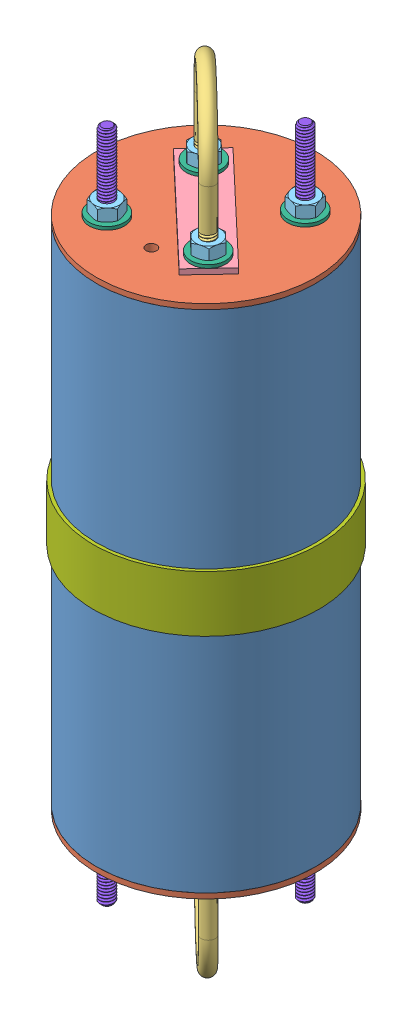
SolidWorks assembly EBayAssembly, configuration Default. Lengths in mm.
Overall size (140.1 352.48 140.1).
55 component instances, 10 part files, 79 mates.
Components (placement in the parent):
- EBayCoupler-1: EBayCoupler [Default] at (144.2445 84.1878 268.749) size (99.1 228.6 99.1)
- EBayBulkheadAssembly-1: EBayBulkheadAssembly [Default] at (219.6286 370.3293 234.3006) x (-0.726253 0 -0.687428) z (-0.687428 0 0.726253) size (99.1 83.11 99.1)
  - EBayBulkhead-1: EBayBulkhead [Default] at (31.0671 55.1815 76.8393) size (99.1 4.72 99.1)
  - 3043T618_U-Bolt-1: 3043T618_U-Bolt [3043T618] at (31.0671 24.1754 76.8393) size (63.63 83.11 11.11)
  - 8875T929_Mount Plate for 1 4 -20 Thread-1: 8875T929_Mount Plate for 1 4 -20 Thread [8875T929] at (31.0671 59.9015 76.8393) x (1 0 0) z (0 1 0) size (66.67 19.05 2.38)
  - 91845A029_18-8 Stainless Steel Hex Nut-1: 91845A029_18-8 Stainless Steel Hex Nut [91845A029] at (5.6671 48.5743 76.8393) x (0.866025 0 0.5) z (0 -1 0) size (11.11 12.83 6.51)
  - 92141A029_18-8 Stainless Steel Washer-1: 92141A029_18-8 Stainless Steel Washer [92141A029] at (5.6671 51.3525 76.8393) size (15.88 1.45 15.88)
  - 92141A029_18-8 Stainless Steel Washer-2: 92141A029_18-8 Stainless Steel Washer [92141A029] at (56.4671 51.3525 76.8393) size (15.88 1.45 15.88)
  - 92141A029_18-8 Stainless Steel Washer-3: 92141A029_18-8 Stainless Steel Washer [92141A029] at (56.4671 62.2828 76.8393) size (15.88 1.45 15.88)
  - 92141A029_18-8 Stainless Steel Washer-4: 92141A029_18-8 Stainless Steel Washer [92141A029] at (5.6671 62.2828 76.8393) size (15.88 1.45 15.88)
  - 91845A029_18-8 Stainless Steel Hex Nut-2: 91845A029_18-8 Stainless Steel Hex Nut [91845A029] at (56.4671 48.5743 76.8393) x (0.866025 0 -0.5) z (0 -1 0) size (11.11 12.83 6.51)
  - 8875T929_Mount Plate for 1 4 -20 Thread-2: 8875T929_Mount Plate for 1 4 -20 Thread [8875T929] at (31.0671 55.1815 76.8393) x (1 0 0) z (0 -1 0) size (66.67 19.05 2.38)
- EBayBulkheadAssembly-2: EBayBulkheadAssembly [Default] at (113.9857 26.6463 345.9101) x (-0.726253 0 -0.687428) z (0.687428 0 -0.726253) size (99.1 83.11 99.1)
  - EBayBulkhead-1: EBayBulkhead [Default] at (31.0671 55.1815 76.8393) size (99.1 4.72 99.1)
  - 3043T618_U-Bolt-1: 3043T618_U-Bolt [3043T618] at (31.0671 24.1754 76.8393) size (63.63 83.11 11.11)
  - 8875T929_Mount Plate for 1 4 -20 Thread-1: 8875T929_Mount Plate for 1 4 -20 Thread [8875T929] at (31.0671 59.9015 76.8393) x (1 0 0) z (0 1 0) size (66.67 19.05 2.38)
  - 91845A029_18-8 Stainless Steel Hex Nut-1: 91845A029_18-8 Stainless Steel Hex Nut [91845A029] at (5.6671 48.5743 76.8393) x (0.866025 0 0.5) z (0 -1 0) size (11.11 12.83 6.51)
  - 92141A029_18-8 Stainless Steel Washer-1: 92141A029_18-8 Stainless Steel Washer [92141A029] at (5.6671 51.3525 76.8393) size (15.88 1.45 15.88)
  - 92141A029_18-8 Stainless Steel Washer-2: 92141A029_18-8 Stainless Steel Washer [92141A029] at (56.4671 51.3525 76.8393) size (15.88 1.45 15.88)
  - 92141A029_18-8 Stainless Steel Washer-3: 92141A029_18-8 Stainless Steel Washer [92141A029] at (56.4671 62.2828 76.8393) size (15.88 1.45 15.88)
  - 92141A029_18-8 Stainless Steel Washer-4: 92141A029_18-8 Stainless Steel Washer [92141A029] at (5.6671 62.2828 76.8393) size (15.88 1.45 15.88)
  - 91845A029_18-8 Stainless Steel Hex Nut-2: 91845A029_18-8 Stainless Steel Hex Nut [91845A029] at (56.4671 48.5743 76.8393) x (0.866025 0 -0.5) z (0 -1 0) size (11.11 12.83 6.51)
  - 8875T929_Mount Plate for 1 4 -20 Thread-2: 8875T929_Mount Plate for 1 4 -20 Thread [8875T929] at (31.0671 55.1815 76.8393) x (1 0 0) z (0 -1 0) size (66.67 19.05 2.38)
- SwitchBand-1: SwitchBand [Default] at (144.2445 185.7878 268.749) size (102 25.4 102)
- 91845A029_18-8 Stainless Steel Hex Nut-1: 91845A029_18-8 Stainless Steel Hex Nut [91845A029] at (122.4187 306.2019 291.8075) x (-0.232204 0 0.972667) z (0 -1 0) size (11.11 12.83 6.51)
- 92141A029_18-8 Stainless Steel Washer-1: 92141A029_18-8 Stainless Steel Washer [92141A029] at (122.4187 315.1478 291.8075) size (15.88 1.45 15.88)
- ThreadedRod-1: ThreadedRod [95475A576] at (122.4187 198.4878 291.8075) x (0 -1 0) z (0 0 1) size (307.18 6.43 7.33)
- ThreadedRod-2: ThreadedRod [95475A576] at (166.0704 198.4878 245.6904) x (0 -1 0) z (0 0 1) size (307.18 6.43 7.33)
- 92141A029_18-8 Stainless Steel Washer-2: 92141A029_18-8 Stainless Steel Washer [92141A029] at (166.0704 308.98 245.6904) x (0.999179 0 0.04051) z (-0.04051 0 0.999179) size (15.88 1.45 15.88)
- 92141A029_18-8 Stainless Steel Washer-3: 92141A029_18-8 Stainless Steel Washer [92141A029] at (166.0704 315.1478 245.6904) size (15.88 1.45 15.88)
- 92141A029_18-8 Stainless Steel Washer-4: 92141A029_18-8 Stainless Steel Washer [92141A029] at (122.4187 308.98 291.8075) size (15.88 1.45 15.88)
- 91845A029_18-8 Stainless Steel Hex Nut-2: 91845A029_18-8 Stainless Steel Hex Nut [91845A029] at (166.0704 306.2019 245.6904) x (0.726253 0 0.687428) z (0 -1 0) size (11.11 12.83 6.51)
- 91845A029_18-8 Stainless Steel Hex Nut-3: 91845A029_18-8 Stainless Steel Hex Nut [91845A029] at (166.0704 319.3737 245.6904) x (0.726253 0 0.687428) z (0 -1 0) size (11.11 12.83 6.51)
- 91845A029_18-8 Stainless Steel Hex Nut-4: 91845A029_18-8 Stainless Steel Hex Nut [91845A029] at (122.4187 319.3737 291.8075) x (0.726253 0 0.687428) z (0 -1 0) size (11.11 12.83 6.51)
- 91845A029_18-8 Stainless Steel Hex Nut-5: 91845A029_18-8 Stainless Steel Hex Nut [91845A029] at (166.0704 77.6019 245.6904) x (0.726253 0 0.687428) z (0 -1 0) size (11.11 12.83 6.51)
- 92141A029_18-8 Stainless Steel Washer-5: 92141A029_18-8 Stainless Steel Washer [92141A029] at (122.4187 86.5478 291.8075) size (15.88 1.45 15.88)
- 91845A029_18-8 Stainless Steel Hex Nut-7: 91845A029_18-8 Stainless Steel Hex Nut [91845A029] at (122.4187 77.6019 291.8075) x (0.958456 0 -0.285239) z (0 -1 0) size (11.11 12.83 6.51)
- 91845A029_18-8 Stainless Steel Hex Nut-8: 91845A029_18-8 Stainless Steel Hex Nut [91845A029] at (122.4187 90.7737 291.8075) x (-0.726253 0 -0.687428) z (0 -1 0) size (11.11 12.83 6.51)
- 91845A029_18-8 Stainless Steel Hex Nut-9: 91845A029_18-8 Stainless Steel Hex Nut [91845A029] at (166.0704 90.7737 245.6904) x (0.958456 0 -0.285239) z (0 -1 0) size (11.11 12.83 6.51)
- 92141A029_18-8 Stainless Steel Washer-7: 92141A029_18-8 Stainless Steel Washer [92141A029] at (166.0704 86.5478 245.6904) size (15.88 1.45 15.88)
- 92141A029_18-8 Stainless Steel Washer-8: 92141A029_18-8 Stainless Steel Washer [92141A029] at (122.4187 80.38 291.8075) size (15.88 1.45 15.88)
- 92141A029_18-8 Stainless Steel Washer-9: 92141A029_18-8 Stainless Steel Washer [92141A029] at (166.0704 80.38 245.6904) size (15.88 1.45 15.88)
- EBaySled-1: EBaySled [Default] at (144.2445 123.4878 268.749) x (0.687428 0 -0.726253) z (0.726253 0 0.687428) size (75.5 150 22)
- M3HeatInsert_94180A331-1: M3HeatInsert_94180A331 [94180A331] at (155.815 200.4878 262.4893) x (0.687428 0 -0.726253) z (0.726253 0 0.687428) size (5.56 5.56 3.99)
- M3HeatInsert_94180A331-2: M3HeatInsert_94180A331 [94180A331] at (138.6293 200.4878 280.6456) x (0.687428 0 -0.726253) z (0.726253 0 0.687428) size (5.56 5.56 3.99)
- M3HeatInsert_94180A331-3: M3HeatInsert_94180A331 [94180A331] at (155.815 216.4878 262.4893) x (0.687428 0 -0.726253) z (0.726253 0 0.687428) size (5.56 5.56 3.99)
- M3HeatInsert_94180A331-4: M3HeatInsert_94180A331 [94180A331] at (138.6293 216.4878 280.6456) x (0.687428 0 -0.726253) z (0.726253 0 0.687428) size (5.56 5.56 3.99)
- M3HeatInsert_94180A331-5: M3HeatInsert_94180A331 [94180A331] at (152.0939 157.4878 254.492) x (-0.634996 -0.383049 0.67086) z (-0.726253 0 -0.687428) size (5.56 5.56 3.99)
- M3HeatInsert_94180A331-6: M3HeatInsert_94180A331 [94180A331] at (149.9972 264.6878 256.7071) x (-0.687428 0 0.726253) z (-0.726253 0 -0.687428) size (5.56 5.56 3.99)
- M3HeatInsert_94180A331-7: M3HeatInsert_94180A331 [94180A331] at (130.4399 157.4878 277.369) x (-0.634996 -0.383049 0.67086) z (-0.726253 0 -0.687428) size (5.56 5.56 3.99)
- M3HeatInsert_94180A331-8: M3HeatInsert_94180A331 [94180A331] at (152.0939 143.4878 254.492) x (-0.634996 -0.383049 0.67086) z (-0.726253 0 -0.687428) size (5.56 5.56 3.99)
- M3HeatInsert_94180A331-9: M3HeatInsert_94180A331 [94180A331] at (132.5366 264.6878 275.1539) x (-0.634996 -0.383049 0.67086) z (-0.726253 0 -0.687428) size (5.56 5.56 3.99)
- M3HeatInsert_94180A331-10: M3HeatInsert_94180A331 [94180A331] at (132.5366 188.4878 275.1539) x (0.634996 0.383049 -0.67086) z (-0.726253 0 -0.687428) size (5.56 5.56 3.99)
- M3HeatInsert_94180A331-11: M3HeatInsert_94180A331 [94180A331] at (149.9972 188.4878 256.7071) x (0.634996 0.383049 -0.67086) z (-0.726253 0 -0.687428) size (5.56 5.56 3.99)
- M3HeatInsert_94180A331-13: M3HeatInsert_94180A331 [94180A331] at (130.4399 143.4878 277.369) x (-0.634996 -0.383049 0.67086) z (-0.726253 0 -0.687428) size (5.56 5.56 3.99)
Mates (geometry in assembly coordinates):
- Concentric1: concentric aligned: cylinder of EBayCoupler-1 through (144.2445 312.7878 268.749) axis (0 -1 0) radius 49.55; cylinder of SwitchBand-1 through (144.2445 211.1878 268.749) axis (0 -1 0) radius 49.55
- Width1: width aligned: plane of EBayCoupler-1 through (144.2445 312.7878 268.749) normal (0 1 0); plane of EBayCoupler-1 through (144.2445 84.1878 268.749) normal (0 -1 0); plane of SwitchBand-1 through (144.2445 211.1878 268.749) normal (0 1 0); plane of SwitchBand-1 through (144.2445 185.7878 268.749) normal (0 -1 0)
- Concentric2: concentric anti-aligned: cylinder of EBayCoupler-1 through (144.2445 312.7878 268.749) axis (0 -1 0) radius 47.95; cylinder of EBayBulkheadAssembly-1/EBayBulkhead-1 through (144.2445 310.4278 268.749) axis (0 1 0) radius 47.95
- Coincident1: coincident anti-aligned: plane of EBayCoupler-1 through (144.2445 312.7878 268.749) normal (0 1 0); plane of EBayBulkheadAssembly-1/EBayBulkhead-1 through (144.2445 312.7878 268.749) normal (0 -1 0)
- Concentric3: concentric aligned: cylinder of EBayCoupler-1 through (144.2445 312.7878 268.749) axis (0 -1 0) radius 47.95; cylinder of EBayBulkheadAssembly-2/EBayBulkhead-1 through (144.2445 86.5478 268.749) axis (0 -1 0) radius 47.95
- Coincident2: coincident anti-aligned: plane of EBayCoupler-1 through (144.2445 84.1878 268.749) normal (0 -1 0); plane of EBayBulkheadAssembly-2/EBayBulkhead-1 through (144.2445 84.1878 268.749) normal (0 1 0)
- Concentric4: concentric anti-aligned: cylinder of EBayBulkheadAssembly-1/EBayBulkhead-1 through (122.4187 310.4278 291.8075) axis (0 1 0) radius 3.175; circle of ThreadedRod-1
- Concentric5: concentric anti-aligned: cylinder of EBayBulkheadAssembly-1/EBayBulkhead-1 through (166.0704 310.4278 245.6904) axis (0 1 0) radius 3.175; circle of ThreadedRod-2
- Width2: width aligned: plane of EBayBulkheadAssembly-1/EBayBulkhead-1 through (144.2445 315.1478 268.749) normal (0 1 0); plane of ThreadedRod-1 through (144.2445 81.8278 268.749) normal (0 -1 0); plane of EBayBulkheadAssembly-2/EBayBulkhead-1 through (122.4187 350.8878 291.8075) normal (0 1 0); plane of ThreadedRod-1 through (122.4187 46.0878 291.8075) normal (0 -1 0)
- Width3: width aligned: plane of EBayBulkheadAssembly-1/EBayBulkhead-1 through (144.2445 315.1478 268.749) normal (0 1 0); plane of ThreadedRod-2 through (144.2445 81.8278 268.749) normal (0 -1 0); plane of EBayBulkheadAssembly-2/EBayBulkhead-1 through (166.0704 350.8878 245.6904) normal (0 1 0); plane of ThreadedRod-2 through (166.0704 46.0878 245.6904) normal (0 -1 0)
- Concentric6: concentric aligned: cylinder of ThreadedRod-2 through (166.0704 46.0878 245.6904) axis (0 1 0) radius 3.175; circle of 92141A029_18-8 Stainless Steel Washer-2
- Concentric7: concentric aligned: cylinder of ThreadedRod-1 through (122.4187 46.0878 291.8075) axis (0 1 0) radius 3.175; circle of 92141A029_18-8 Stainless Steel Washer-4
- Concentric8: concentric aligned: cylinder of ThreadedRod-2 through (166.0704 46.0878 245.6904) axis (0 1 0) radius 3.175; circle of 92141A029_18-8 Stainless Steel Washer-3
- Concentric9: concentric aligned: circle of 92141A029_18-8 Stainless Steel Washer-1; cylinder of ThreadedRod-1 through (122.4187 46.0878 291.8075) axis (0 1 0) radius 3.175
- Coincident3: coincident anti-aligned: cylinder of ThreadedRod-1 through (122.4187 46.0878 291.8075) axis (0 1 0) radius 3.175; circle of 91845A029_18-8 Stainless Steel Hex Nut-4
- Coincident4: coincident anti-aligned: circle of 91845A029_18-8 Stainless Steel Hex Nut-1; cylinder of ThreadedRod-1 through (122.4187 46.0878 291.8075) axis (0 1 0) radius 3.175
- Coincident5: coincident anti-aligned: cylinder of ThreadedRod-2 through (166.0704 46.0878 245.6904) axis (0 1 0) radius 3.175; circle of 91845A029_18-8 Stainless Steel Hex Nut-2
- Coincident6: coincident anti-aligned: cylinder of ThreadedRod-2 through (166.0704 46.0878 245.6904) axis (0 1 0) radius 3.175; circle of 91845A029_18-8 Stainless Steel Hex Nut-3
- Coincident7: coincident anti-aligned: plane of 92141A029_18-8 Stainless Steel Washer-1 through (122.4187 316.5956 291.8075) normal (0 1 0); plane of 91845A029_18-8 Stainless Steel Hex Nut-4 through (116.1783 316.5956 290.3177) normal (0 -1 0)
- Coincident8: coincident anti-aligned: plane of 91845A029_18-8 Stainless Steel Hex Nut-1 through (120.5887 308.98 285.6582) normal (0 1 0); plane of 92141A029_18-8 Stainless Steel Washer-4 through (122.4187 308.98 291.8075) normal (0 -1 0)
- Coincident9: coincident anti-aligned: plane of 92141A029_18-8 Stainless Steel Washer-3 through (166.0704 316.5956 245.6904) normal (0 1 0); plane of 91845A029_18-8 Stainless Steel Hex Nut-3 through (159.8299 316.5956 244.2007) normal (0 -1 0)
- Coincident10: coincident anti-aligned: plane of 92141A029_18-8 Stainless Steel Washer-2 through (166.0704 308.98 245.6904) normal (0 -1 0); plane of 91845A029_18-8 Stainless Steel Hex Nut-2 through (159.8299 308.98 244.2007) normal (0 1 0)
- Parallel1: parallel aligned: plane of 91845A029_18-8 Stainless Steel Hex Nut-2 through (172.3108 303.4238 247.1802) normal (0.726253 0 0.687428); plane of 91845A029_18-8 Stainless Steel Hex Nut-3 through (172.3108 316.5956 247.1802) normal (0.726253 0 0.687428)
- Parallel2: parallel aligned: plane of 91845A029_18-8 Stainless Steel Hex Nut-1 through (128.6592 303.4238 293.2973) normal (0.726253 0 0.687428); plane of 91845A029_18-8 Stainless Steel Hex Nut-4 through (128.6592 316.5956 293.2973) normal (0.726253 0 0.687428)
- Coincident13: coincident aligned: plane of 91845A029_18-8 Stainless Steel Hex Nut-1 through (128.6592 303.4238 293.2973) normal (0.726253 0 0.687428); plane of 91845A029_18-8 Stainless Steel Hex Nut-3 through (172.3108 316.5956 247.1802) normal (0.726253 0 0.687428)
- Coincident14: coincident aligned: plane of 92141A029_18-8 Stainless Steel Washer-2 through (166.0704 310.4278 245.6904) normal (0 1 0); plane of 92141A029_18-8 Stainless Steel Washer-4 through (122.4187 310.4278 291.8075) normal (0 1 0)
- Coincident15: coincident anti-aligned: plane of EBayBulkheadAssembly-1/EBayBulkhead-1 through (144.2445 310.4278 268.749) normal (0 -1 0); plane of 92141A029_18-8 Stainless Steel Washer-2 through (166.0704 310.4278 245.6904) normal (0 1 0)
- Coincident16: coincident anti-aligned: plane of 92141A029_18-8 Stainless Steel Washer-1 through (122.4187 315.1478 291.8075) normal (0 -1 0); circle of 92141A029_18-8 Stainless Steel Washer-3
- Coincident17: coincident anti-aligned: plane of EBayBulkheadAssembly-1/EBayBulkhead-1 through (144.2445 315.1478 268.749) normal (0 1 0); plane of 92141A029_18-8 Stainless Steel Washer-3 through (166.0704 315.1478 245.6904) normal (0 -1 0)
- Concentric10: concentric aligned: cylinder of EBayBulkheadAssembly-2/EBayBulkhead-1 through (122.4187 86.5478 291.8075) axis (0 -1 0) radius 3.175; circle of ThreadedRod-1
- Concentric11: concentric aligned: cylinder of EBayBulkheadAssembly-2/EBayBulkhead-1 through (166.0704 86.5478 245.6904) axis (0 -1 0) radius 3.175; circle of ThreadedRod-2
- Concentric12: concentric anti-aligned: circle of ThreadedRod-2; cylinder of 92141A029_18-8 Stainless Steel Washer-7 through (166.0704 86.5478 245.6904) axis (0 1 0) radius 3.5687
- Concentric13: concentric anti-aligned: circle of ThreadedRod-1; cylinder of 92141A029_18-8 Stainless Steel Washer-8 through (122.4187 80.38 291.8075) axis (0 1 0) radius 3.5687
- Concentric14: concentric anti-aligned: circle of ThreadedRod-2; cylinder of 92141A029_18-8 Stainless Steel Washer-9 through (166.0704 80.38 245.6904) axis (0 1 0) radius 3.5687
- Concentric15: concentric anti-aligned: circle of ThreadedRod-1; cylinder of 92141A029_18-8 Stainless Steel Washer-5 through (122.4187 86.5478 291.8075) axis (0 1 0) radius 3.5687
- Concentric16: concentric aligned: circle of ThreadedRod-2; circle of 91845A029_18-8 Stainless Steel Hex Nut-9
- Concentric17: concentric aligned: circle of ThreadedRod-2; circle of 91845A029_18-8 Stainless Steel Hex Nut-5
- Concentric18: concentric aligned: circle of ThreadedRod-1; circle of 91845A029_18-8 Stainless Steel Hex Nut-7
- Concentric19: concentric aligned: circle of ThreadedRod-1; circle of 91845A029_18-8 Stainless Steel Hex Nut-8
- Coincident18: coincident anti-aligned: plane of 92141A029_18-8 Stainless Steel Washer-5 through (122.4187 87.9956 291.8075) normal (0 1 0); plane of 91845A029_18-8 Stainless Steel Hex Nut-8 through (128.6592 87.9956 293.2973) normal (0 -1 0)
- Coincident19: coincident anti-aligned: plane of 91845A029_18-8 Stainless Steel Hex Nut-7 through (118.0083 80.38 296.467) normal (0 1 0); plane of 92141A029_18-8 Stainless Steel Washer-8 through (122.4187 80.38 291.8075) normal (0 -1 0)
- Coincident20: coincident anti-aligned: plane of 91845A029_18-8 Stainless Steel Hex Nut-5 through (159.8299 80.38 244.2007) normal (0 1 0); plane of 92141A029_18-8 Stainless Steel Washer-9 through (166.0704 80.38 245.6904) normal (0 -1 0)
- Coincident22: coincident anti-aligned: plane of 91845A029_18-8 Stainless Steel Hex Nut-9 through (161.66 87.9956 250.3499) normal (0 -1 0); plane of 92141A029_18-8 Stainless Steel Washer-7 through (166.0704 87.9956 245.6904) normal (0 1 0)
- Coincident23: coincident aligned: plane of 92141A029_18-8 Stainless Steel Washer-5 through (122.4187 86.5478 291.8075) normal (0 -1 0); plane of 92141A029_18-8 Stainless Steel Washer-7 through (166.0704 86.5478 245.6904) normal (0 -1 0)
- Coincident24: coincident aligned: plane of 92141A029_18-8 Stainless Steel Washer-8 through (122.4187 81.8278 291.8075) normal (0 1 0); plane of 92141A029_18-8 Stainless Steel Washer-9 through (166.0704 81.8278 245.6904) normal (0 1 0)
- Parallel3: parallel aligned: plane of 91845A029_18-8 Stainless Steel Hex Nut-5 through (159.8299 74.8238 244.2007) normal (-0.726253 0 -0.687428); plane of 91845A029_18-8 Stainless Steel Hex Nut-9 through (159.8299 87.9956 244.2007) normal (-0.726253 0 -0.687428)
- Coincident26: coincident aligned: plane of 91845A029_18-8 Stainless Steel Hex Nut-7 through (116.1783 74.8238 290.3177) normal (-0.726253 0 -0.687428); plane of 91845A029_18-8 Stainless Steel Hex Nut-8 through (116.1783 87.9956 290.3177) normal (-0.726253 0 -0.687428)
- Coincident27: coincident aligned: plane of 91845A029_18-8 Stainless Steel Hex Nut-5 through (159.8299 74.8238 244.2007) normal (-0.726253 0 -0.687428); plane of 91845A029_18-8 Stainless Steel Hex Nut-7 through (116.1783 74.8238 290.3177) normal (-0.726253 0 -0.687428)
- Coincident28: coincident aligned: plane of 91845A029_18-8 Stainless Steel Hex Nut-3 through (159.8299 316.5956 244.2007) normal (-0.726253 0 -0.687428); plane of 91845A029_18-8 Stainless Steel Hex Nut-7 through (116.1783 74.8238 290.3177) normal (-0.726253 0 -0.687428)
- Coincident29: coincident anti-aligned: plane of EBayBulkheadAssembly-2/EBayBulkhead-1 through (144.2445 81.8278 268.749) normal (0 -1 0); plane of 92141A029_18-8 Stainless Steel Washer-8 through (122.4187 81.8278 291.8075) normal (0 1 0)
- Coincident30: coincident anti-aligned: plane of EBayBulkheadAssembly-2/EBayBulkhead-1 through (144.2445 86.5478 268.749) normal (0 1 0); plane of 92141A029_18-8 Stainless Steel Washer-5 through (122.4187 86.5478 291.8075) normal (0 -1 0)
- Concentric20: concentric anti-aligned: circle of EBaySled-1; circle of M3HeatInsert_94180A331-2
- Concentric21: concentric anti-aligned: circle of EBaySled-1; circle of M3HeatInsert_94180A331-1
- Concentric23: concentric anti-aligned: circle of EBaySled-1; circle of M3HeatInsert_94180A331-4
- Coincident39: coincident aligned: plane of EBaySled-1 through (148.6021 274.5604 272.8735) normal (0.726253 0 0.687428); plane of M3HeatInsert_94180A331-4 through (140.0092 219.0604 281.9517) normal (0.726253 0 0.687428)
- Coincident40: coincident aligned: plane of EBaySled-1 through (148.6021 274.5604 272.8735) normal (0.726253 0 0.687428); plane of M3HeatInsert_94180A331-3 through (157.1949 219.0604 263.7954) normal (0.726253 0 0.687428)
- Coincident41: coincident aligned: plane of EBaySled-1 through (148.6021 274.5604 272.8735) normal (0.726253 0 0.687428); plane of M3HeatInsert_94180A331-1 through (157.1949 203.0604 263.7954) normal (0.726253 0 0.687428)
- Coincident42: coincident aligned: plane of EBaySled-1 through (148.6021 274.5604 272.8735) normal (0.726253 0 0.687428); plane of M3HeatInsert_94180A331-2 through (140.0092 203.0604 281.9517) normal (0.726253 0 0.687428)
- Coincident44: coincident aligned: plane of EBaySled-1 through (139.887 274.5604 264.6244) normal (-0.726253 0 -0.687428); plane of M3HeatInsert_94180A331-11 through (149.0123 188.1748 254.9837) normal (-0.726253 0 -0.687428)
- Coincident45: coincident aligned: plane of EBaySled-1 through (139.887 274.5604 264.6244) normal (-0.726253 0 -0.687428); plane of M3HeatInsert_94180A331-10 through (131.5517 188.1748 273.4305) normal (-0.726253 0 -0.687428)
- Coincident46: coincident aligned: plane of EBaySled-1 through (139.887 274.5604 264.6244) normal (-0.726253 0 -0.687428); plane of M3HeatInsert_94180A331-6 through (148.6174 267.2604 255.401) normal (-0.726253 0 -0.687428)
- Coincident47: coincident aligned: plane of EBaySled-1 through (139.887 274.5604 264.6244) normal (-0.726253 0 -0.687428); plane of M3HeatInsert_94180A331-5 through (150.319 159.946 253.6032) normal (-0.726253 0 -0.687428)
- Coincident48: coincident aligned: plane of EBaySled-1 through (139.887 274.5604 264.6244) normal (-0.726253 0 -0.687428); plane of M3HeatInsert_94180A331-9 through (130.7617 267.146 274.2651) normal (-0.726253 0 -0.687428)
- Coincident49: coincident aligned: plane of EBaySled-1 through (139.887 274.5604 264.6244) normal (-0.726253 0 -0.687428); plane of M3HeatInsert_94180A331-7 through (128.6651 159.946 276.4802) normal (-0.726253 0 -0.687428)
- Coincident50: coincident aligned: plane of EBaySled-1 through (139.887 274.5604 264.6244) normal (-0.726253 0 -0.687428); plane of M3HeatInsert_94180A331-8 through (150.319 145.946 253.6032) normal (-0.726253 0 -0.687428)
- Concentric24: concentric anti-aligned: circle of EBaySled-1; circle of M3HeatInsert_94180A331-10
- Concentric25: concentric anti-aligned: cone of EBaySled-1 through (148.2542 189.5604 255.0573) axis (0.726253 0 0.687428); circle of M3HeatInsert_94180A331-11
- Concentric26: concentric anti-aligned: circle of EBaySled-1; cylinder of M3HeatInsert_94180A331-9 through (131.1567 265.7604 273.8478) axis (-0.726253 0 -0.687428) radius 2.78
- Concentric27: concentric anti-aligned: circle of EBaySled-1; circle of M3HeatInsert_94180A331-6
- Concentric28: concentric anti-aligned: circle of EBaySled-1; circle of M3HeatInsert_94180A331-5
- Concentric29: concentric anti-aligned: circle of EBaySled-1; circle of M3HeatInsert_94180A331-7
- Concentric30: concentric anti-aligned: circle of EBaySled-1; circle of M3HeatInsert_94180A331-8
- Concentric31: concentric anti-aligned: circle of EBaySled-1; circle of M3HeatInsert_94180A331-3
- Concentric32: concentric anti-aligned: circle of EBaySled-1; circle of M3HeatInsert_94180A331-13
- Coincident54: coincident aligned: plane of EBaySled-1 through (139.887 274.5604 264.6244) normal (-0.726253 0 -0.687428); plane of M3HeatInsert_94180A331-13 through (128.6651 145.946 276.4802) normal (-0.726253 0 -0.687428)
- Concentric33: concentric aligned: circle of M3HeatInsert_94180A331-6; cylinder of M3x6Standoff.step-1 through (-89.8895 265.7695 466.7607) axis (0 0 -1) radius 1.5
- Concentric49: concentric anti-aligned: circle of ThreadedRod-2; cylinder of EBaySled-1 through (166.0704 274.5604 245.6904) axis (0 -1 0) radius 3.75
- Concentric50: concentric anti-aligned: circle of ThreadedRod-1; cylinder of EBaySled-1 through (122.4187 274.5604 291.8075) axis (0 -1 0) radius 3.75
- Width4: width aligned: plane of EBaySled-1 through (144.2445 273.4878 268.749) normal (0 1 0); plane of EBayBulkheadAssembly-2/EBayBulkhead-1 through (144.2445 123.4878 268.749) normal (0 -1 0); plane of EBaySled-1 through (144.2445 86.5478 268.749) normal (0 1 0); plane of EBayBulkheadAssembly-1/EBayBulkhead-1 through (144.2445 310.4278 268.749) normal (0 -1 0)
